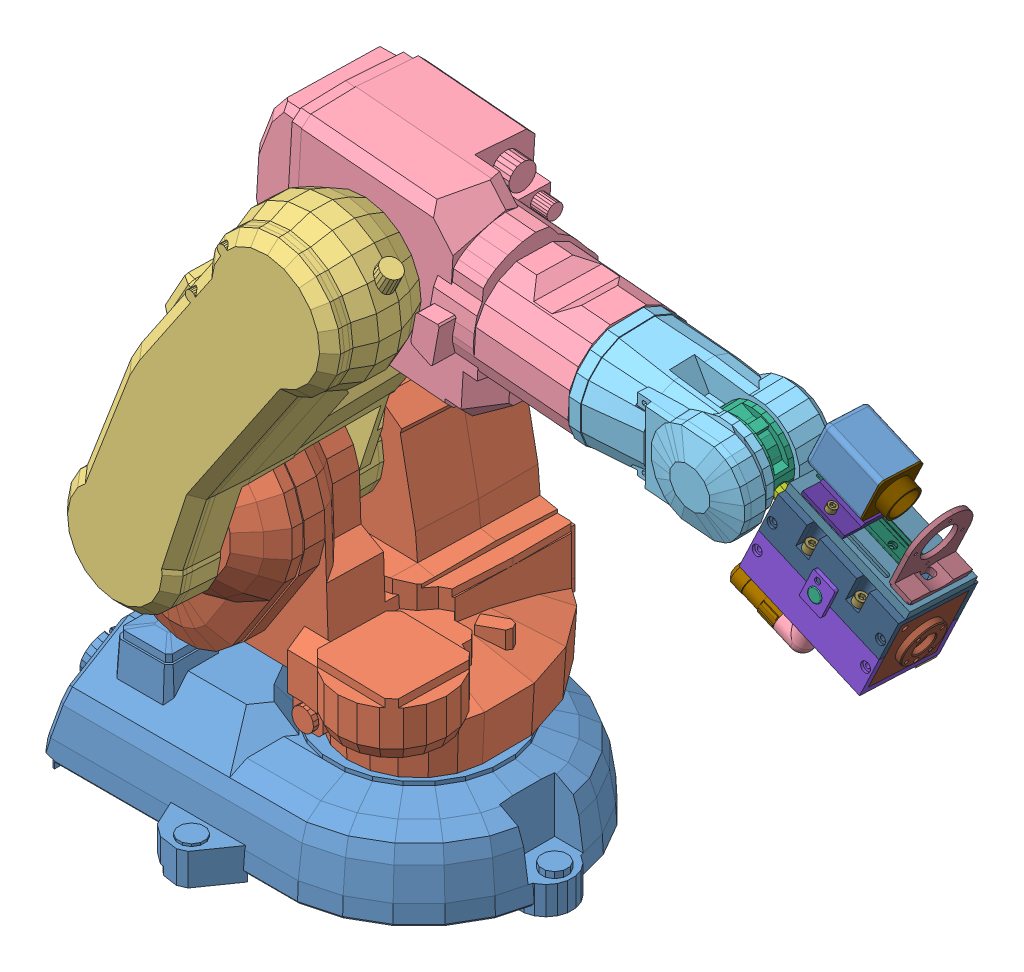
SolidWorks assembly abb_robot, configuration Default. Lengths in mm.
Overall size (1167.55 810.84 478.94).
47 component instances, 29 part files, 15 mates.
Components (placement in the parent):
- IRB140_-_M2000_REV2_01-1-1: IRB140_-_M2000_REV2_01-1 [Default] at (43.9429 -9.5 -28.3409) x (1 0 0) z (0 1 0) size (487.68 401.97 152.5)
- IRB140_-_M2000_REV2_01-2-1: IRB140_-_M2000_REV2_01-2 [Default] at (43.9429 11 -28.3409) x (-0.999745 0 -0.022591) z (0 1 0) size (341.14 322.3 363)
- IRB140_-_M2000_REV2_01-7-1: IRB140_-_M2000_REV2_01-7 [Default] at (-261.3532 90.1691 62.4103) x (0.872097 -0.488936 0.019707) z (0.488812 0.872319 0.011046) size (182 273.5 515.07)
- IRB140_-_M2000_REV2_01-8-1: IRB140_-_M2000_REV2_01-8 [Default] at (34.1507 -29.3221 69.5879) x (0.997858 -0.061414 0.022549) z (0.061398 0.998112 0.001387) size (386.65 168 200)
- IRB140_-_M2000_REV2_01-9-1: IRB140_-_M2000_REV2_01-9 [Default] at (35.0215 -30.1184 28.8835) x (0.997858 -0.061414 0.022549) z (0.060009 0.996487 0.058414) size (196.5 126 112)
- IRB140_-_M2000_REV2_01-10-1: IRB140_-_M2000_REV2_01-10 [Default] at (393.6829 1482.2855 124.5442) x (0.918834 -0.394642 0.001475) z (-0.393783 -0.917068 -0.062624) size (84 29 84)
- IRB140_-_M2000_REV2_01-11-1: IRB140_-_M2000_REV2_01-11 [Default] at (398.9918 1479.0638 23.2497) x (0.918834 -0.394642 0.001475) z (-0.393497 -0.915868 0.079656) size (29 50 50)
- Montagem_2-1: Montagem_2 [Default] at (610.5385 580.0863 24.5128) x (0.030095 0.073795 0.996819) z (-0.918834 0.394642 -0.001475) size (252.41 221.55 340.17)
  - Estrutura_bottom-1: Estrutura_bottom [Default] at (58.6974 -11.7987 40.1528) size (94 47 150)
  - Acoplamento_robot_50mm-1: Acoplamento_robot_50mm [Default] at (58.6974 28.2013 25.1528) size (80 80 89.49)
  - Estrutura_top-1: Estrutura_top [Default] at (58.6974 75.2013 40.1528) x (-1 0 0) z (0 0 1) size (94 47 150)
  - robot_fix-2: robot_fix [Default] at (58.6974 28.2013 -94.8472) size (80 80 102.04)
  - Socket Head Cap Screw_ISO-2: Socket Head Cap Screw_ISO [ISO 4762 M8 x 40 --- 28C] at (19.6974 56.2013 -65.8472) x (0 -1 0) z (0 0 1) size (48 13 13)
  - Socket Head Cap Screw_ISO-3: Socket Head Cap Screw_ISO [ISO 4762 M8 x 40 --- 28C] at (97.6974 56.2013 -65.8472) x (0 -1 0) z (0 0 1) size (48 13 13)
  - Socket Head Cap Screw_ISO-4: Socket Head Cap Screw_ISO [ISO 4762 M8 x 40 --- 28C] at (97.6974 56.2013 -3.8472) x (0 -1 0) z (0 0 1) size (48 13 13)
  - Socket Head Cap Screw_ISO-5: Socket Head Cap Screw_ISO [ISO 4762 M8 x 40 --- 28C] at (19.6974 56.2013 -3.8472) x (0 -1 0) z (0 0 1) size (48 13 13)
  - Acoplamento_garra_50mm-2: Acoplamento_garra_50mm [Default] at (58.6974 28.2013 53.1528) size (60 60 102.04) (hidden)
  - Socket Head Cap Screw_ISO-6: Socket Head Cap Screw_ISO [ISO 4762 M6 x 12 --- 12C] at (72.8395 42.3434 21.1528) x (0 0 1) z (-1 0 0) size (18 10 10)
  - Socket Head Cap Screw_ISO-7: Socket Head Cap Screw_ISO [ISO 4762 M6 x 12 --- 12C] at (44.5553 42.3434 21.1528) x (0 0 1) z (-1 0 0) size (18 10 10)
  - Socket Head Cap Screw_ISO-8: Socket Head Cap Screw_ISO [ISO 4762 M6 x 12 --- 12C] at (72.8395 14.0591 21.1528) x (0 0 1) z (-1 0 0) size (18 10 10)
  - Socket Head Cap Screw_ISO-9: Socket Head Cap Screw_ISO [ISO 4762 M6 x 12 --- 12C] at (44.5553 14.0591 21.1528) x (0 0 1) z (-1 0 0) size (18 10 10)
  - garra_teste-1: garra_teste [Default] at (58.6974 28.2013 -125.8472) size (240 80 165.45) (hidden)
  - Socket Head Cap Screw_ISO-10: Socket Head Cap Screw_ISO [ISO 4762 M6 x 12 --- 12C] at (72.8395 14.0591 -125.8472) x (0 0 1) z (-1 0 0) size (18 10 10) (hidden)
  - Socket Head Cap Screw_ISO-11: Socket Head Cap Screw_ISO [ISO 4762 M6 x 12 --- 12C] at (44.5553 14.0591 -125.8472) x (0 0 1) z (-1 0 0) size (18 10 10) (hidden)
  - Socket Head Cap Screw_ISO-12: Socket Head Cap Screw_ISO [ISO 4762 M6 x 12 --- 12C] at (44.5553 42.3434 -125.8472) x (0 0 1) z (-1 0 0) size (18 10 10) (hidden)
  - Socket Head Cap Screw_ISO-13: Socket Head Cap Screw_ISO [ISO 4762 M6 x 12 --- 12C] at (72.8395 42.3434 -125.8472) x (0 0 1) z (-1 0 0) size (18 10 10) (hidden)
  - Conjunto_visao-1: Conjunto_visao [Default] at (57.2393 75.2013 -34.8472) x (-1 0 0) z (0 0 -1) size (80 85.3 179.1)
    - Apoio_iluminacaoLEDs-1: Apoio_iluminacaoLEDs [Default] at (0 49.3 49) size (72 79.3 83.14)
    - Apoio_sistema_visao-1: Apoio_sistema_visao [Default] at origin size (80 10 150)
    - Calha_deslizante_27mm-1: Calha_deslizante_27mm [Default] at (0 1.5 44) x (1 0 0) z (0 1 0) size (27 114 8.7)
    - Carro_deslizante_27mm-1: Carro_deslizante_27mm [Default] at (0 1.45 -41.4686) x (1 0 0) z (0 1 0) size (23.9 40 5.35)
    - Apoio_camara_27mm-1: Apoio_camara_27mm [Default] at (0 10 -61.4686) x (-1 0 0) z (0 0 -1) size (54 6.9 52)
    - Camara-1: Camara [Default] at (-9.935 38.5559 -27.3366) size (50.8 57.8 84.8)
      - Encaixe_lente-1: Encaixe_lente [Default] at (9.935 10.7441 16.5114) size (50.8 50.8 16.1)
      - Carapaca-1: Carapaca [Default] at (9.935 10.7441 -17.8386) size (50.8 57.8 68.7)
    - Hex Nut GradeC_ISO-1: Hex Nut GradeC_ISO [Hexagon Nut ISO - 4034 - M6 - C] at (-31 6.5 -35.4686) x (1 0 0) z (0 1 0) size (10 11.55 6.1)
    - Socket Head Cap Screw_ISO-2: Socket Head Cap Screw_ISO [ISO 4762 M6 x 12 --- 12C] at (-31 20 -35.4686) x (0 -1 0) z (-0.997267 0 0.073888) size (18 10 10)
  - Caixa_servo-1: Caixa_servo [Default] at (38.2443 -27.7987 -77.8472) size (25 18 64)
  - Conector_electrico-1: Conector_electrico [Default] at (33.6974 -16.7987 -29.8472) x (0 0 1) z (1 0 0) size (52.9 41.5 25.6)
  - Conector_electrico-2: Conector_electrico [Default] at (83.6974 -16.7987 -29.8472) x (0 0 1) z (1 0 0) size (52.9 41.5 25.6)
  - Conjunto_sensor-1: Conjunto_sensor [Default] at (95.2021 29.691 -33.63) x (0 -1 0) z (0 0 1) size (35 21.4 27)
    - Placa-1: Placa [Default] at (0.0753 1.0047 -1.4363) x (0 0 -1) z (-1 0 0) size (19.9 1.5 22.1)
    - Sensor-1: Sensor [Default] at (0.0753 1.9047 -0.3263) x (0 0 1) z (-1 0 0) size (15.5 18 15.5)
    - Base-1: Base [Default] at (-2.8747 -5.4953 -1.4863) size (35 9.5 27)
    - Tampa2-1: Tampa2 [Default] at (-2.8747 13.0047 -1.4863) x (1 0 0) z (0 0 -1) size (35 15.5 27)
  - Conectror_electrico_plug-1: Conectror_electrico_plug [Default] at (83.6974 -45.7987 -7.6472) x (-0.998562 -0.053604 0) z (0 0 -1) size (25.13 25.13 70.62)
  - Conectror_electrico_plug-2: Conectror_electrico_plug [Default] at (33.6974 -45.7987 -7.6472) x (-0.969923 0.243412 0) z (0 0 -1) size (25.13 25.13 70.62)
Mates (geometry in assembly coordinates):
- Coincident1: coincident anti-aligned: plane of IRB140_-_M2000_REV2_01-1-1 through (43.9429 0 -28.3409) normal (0 -1 0); plane of assembly
- Coincident2: coincident anti-aligned: plane of IRB140_-_M2000_REV2_01-1-1 through (143.9429 100 -28.3409) normal (0 1 0); plane of IRB140_-_M2000_REV2_01-2-1 through (-16.5843 100 0.796) normal (0 -1 0)
- Concentric1: concentric anti-aligned: circle of IRB140_-_M2000_REV2_01-1-1; circle of IRB140_-_M2000_REV2_01-2-1
- Concentric2: concentric anti-aligned: circle of IRB140_-_M2000_REV2_01-2-1; circle of IRB140_-_M2000_REV2_01-7-1
- Width1: width: plane of IRB140_-_M2000_REV2_01-2-1 through (59.8062 348.8514 0.2748) normal (-0.022591 0 0.999745); plane of IRB140_-_M2000_REV2_01-2-1 through (-44.0966 313.7185 34.6863) normal (0.022591 0 -0.999745); plane of IRB140_-_M2000_REV2_01-7-1 through (-53.6609 315.0224 2.0869) normal (0.022591 0 -0.999745); plane of IRB140_-_M2000_REV2_01-7-1 through (-159.67 353.3027 27.6985) normal (-0.022591 0 0.999745)
- Concentric3: concentric anti-aligned: circle of IRB140_-_M2000_REV2_01-7-1; circle of IRB140_-_M2000_REV2_01-8-1
- Coincident4: coincident anti-aligned: plane of IRB140_-_M2000_REV2_01-7-1 through (-29.7244 363 133.1611) normal (0.022591 0 -0.999745); plane of IRB140_-_M2000_REV2_01-8-1 through (115.3142 678.9388 136.4385) normal (-0.022591 0 0.999745)
- Coincident5: coincident aligned: line of IRB140_-_M2000_REV2_01-8-1 through (217.0719 672.536 73.7213) axis (0.997858 -0.061414 0.022549); line of IRB140_-_M2000_REV2_01-9-1 through (363.1043 663.5483 77.0212) axis (0.997858 -0.061414 0.022549)
- Coincident6: coincident anti-aligned: plane of IRB140_-_M2000_REV2_01-8-1 through (390.0578 744.9019 109.6522) normal (0.997858 -0.061414 0.022549); plane of IRB140_-_M2000_REV2_01-9-1 through (382.674 646.2488 167.7211) normal (-0.997858 0.061414 -0.022549)
- Concentric4: concentric aligned: circle of IRB140_-_M2000_REV2_01-9-1; circle of IRB140_-_M2000_REV2_01-10-1
- Width2: width: plane of IRB140_-_M2000_REV2_01-9-1 through (485.7026 623.4477 91.9619) normal (0.026057 0.056936 -0.998038); plane of IRB140_-_M2000_REV2_01-9-1 through (486.4322 625.0419 64.0169) normal (-0.026057 -0.056936 0.998038); plane of IRB140_-_M2000_REV2_01-10-1 through (513.4115 620.6554 93.027) normal (-0.026057 -0.056936 0.998038); plane of IRB140_-_M2000_REV2_01-10-1 through (468.392 661.1135 65.1027) normal (0.026057 0.056936 -0.998038)
- Coincident7: coincident anti-aligned: circle of IRB140_-_M2000_REV2_01-10-1; circle of IRB140_-_M2000_REV2_01-11-1
- Concentric6: concentric aligned: cylinder of IRB140_-_M2000_REV2_01-11-1 through (592.0213 623.7246 80.726) axis (-0.918834 0.394642 -0.001475) radius 12.5; cylinder of Montagem_2-1/Acoplamento_robot_50mm-1 through (592.0213 623.7246 80.726) axis (-0.918834 0.394642 -0.001475) radius 12.5
- Concentric7: concentric anti-aligned: cylinder of IRB140_-_M2000_REV2_01-11-1 through (575.8819 608.9591 82.3063) axis (0.918834 -0.394642 0.001475) radius 3; cylinder of Montagem_2-1/Acoplamento_robot_50mm-1 through (584.1514 605.4073 82.3196) axis (-0.918834 0.394642 -0.001475) radius 3
- Coincident8: coincident anti-aligned: plane of IRB140_-_M2000_REV2_01-11-1 through (586.5083 626.0925 80.7171) normal (0.918834 -0.394642 0.001475); plane of Montagem_2-1/Acoplamento_robot_50mm-1 through (569.5647 586.506 44.0316) normal (-0.918834 0.394642 -0.001475)
